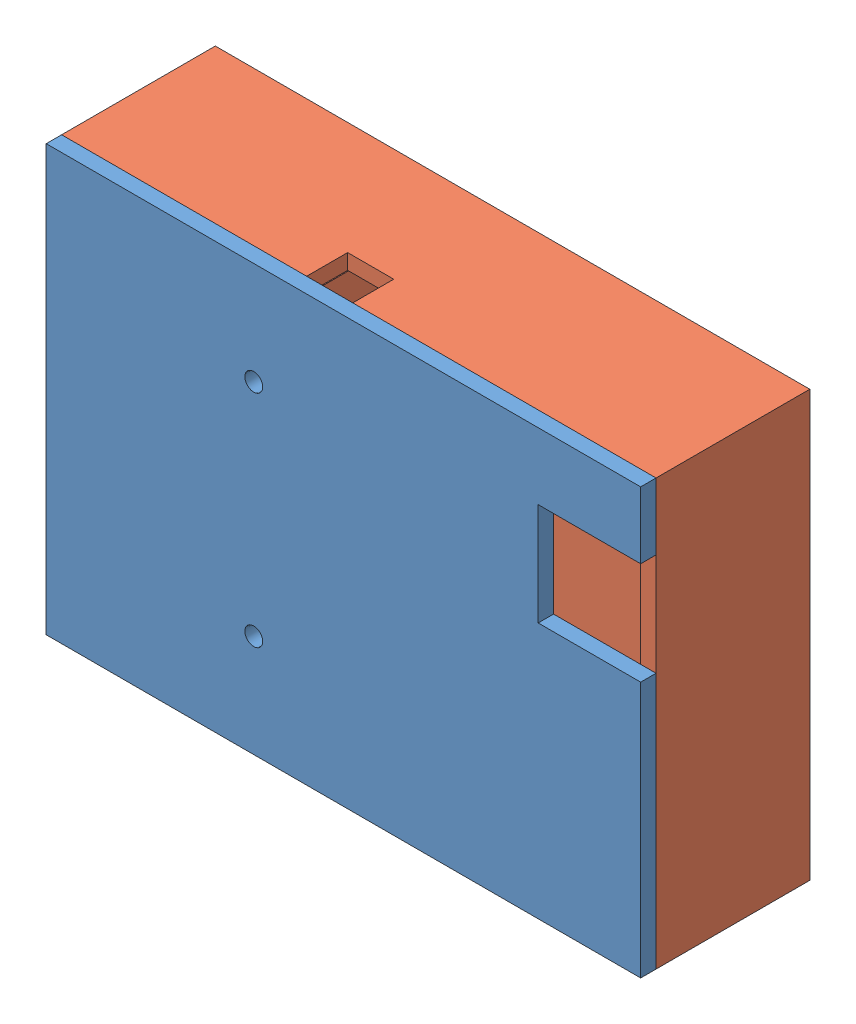
SolidWorks assembly EBoxAssembly_final, configuration Default. Lengths in mm.
Overall size (116 83 33).
2 component instances, 2 part files, 3 mates.
Components (placement in the parent):
- BoxCover_final-1: BoxCover_final [Default] at (25.2912 -40.6746 15.1992) size (116 83 3)
- OuterBox_final-1: OuterBox_final [Default] at (25.2912 -40.6746 -14.8008) size (116 83 30)
Mates (geometry in assembly coordinates):
- Distance1: distance = 0 mm: plane of BoxCover_final-1 through (25.2912 -40.6746 15.1992) normal (0 0 -1); plane of OuterBox_final-1 through (25.2912 -40.6746 15.1992) normal (0 0 1)
- Distance2: distance = 0 mm: plane of BoxCover_final-1 through (-90.7088 42.3254 18.1992) normal (0 1 0); plane of OuterBox_final-1 through (-90.7088 42.3254 15.1992) normal (0 1 0)
- Distance3: distance = 0 mm aligned: plane of OuterBox_final-1 through (25.2912 42.3254 15.1992) normal (1 0 0); plane of BoxCover_final-1 through (25.2912 42.3254 18.1992) normal (1 0 0)
